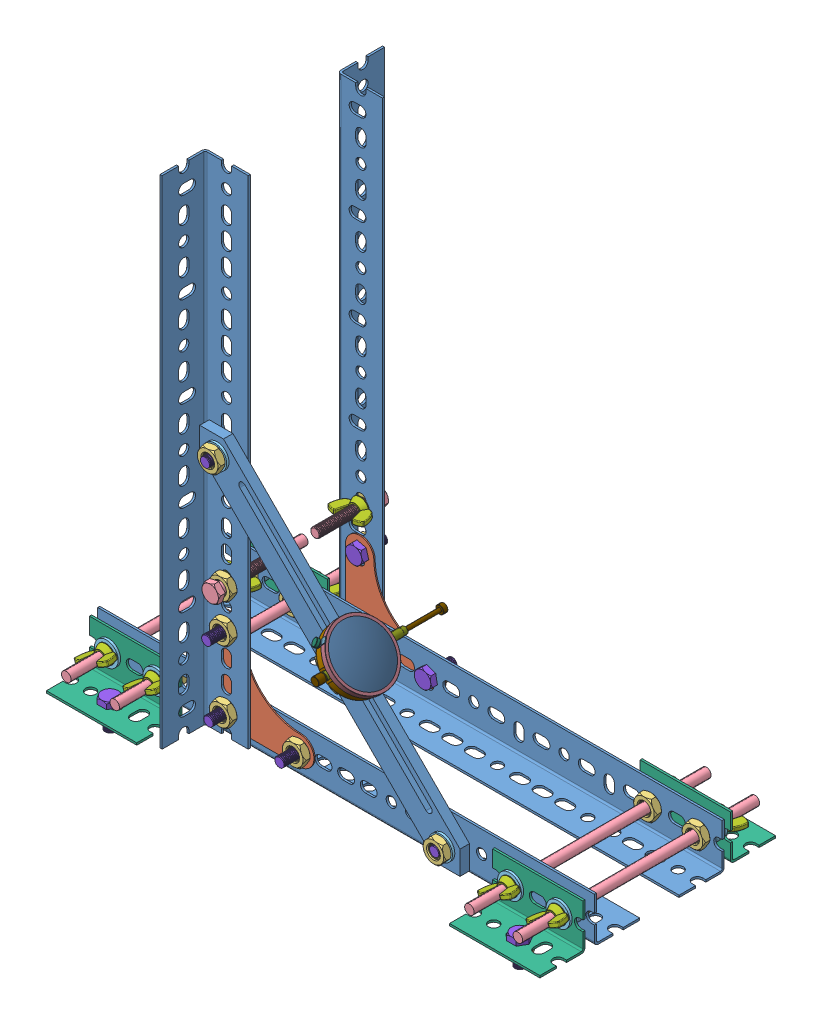
SolidWorks assembly WheelTruingStand, configuration Default. Lengths in mm.
Overall size (419.1 438.26 204.12).
125 component instances, 22 part files, 178 mates.
Components (placement in the parent):
- UprightsSlottedAngle-1: UprightsSlottedAngle [Default] at (103.66 10.7722 357.4461) size (38.1 419.1 38.1)
- UprightsSlottedAngle-2: UprightsSlottedAngle [Default] at (103.66 10.7722 468.9248) x (0 0 1) z (-1 0 0) size (38.1 419.1 38.1)
- UprightsSlottedAngle-3: UprightsSlottedAngle [Default] at (12.0168 9.9594 467.9248) x (0 0 -1) z (0 -1 0) size (38.1 419.1 38.1)
- UprightsSlottedAngle-4: UprightsSlottedAngle [Default] at (12.0168 9.9594 358.4461) x (0 1 0) z (0 0 -1) size (38.1 419.1 38.1)
- 90^CornerPlateSlottedAngle-1: 90^CornerPlateSlottedAngle [Default] at (12.0168 9.9594 467.9248) x (0 -1 0) z (0 0 1) size (83.94 83.94 1)
- 90^CornerPlateSlottedAngle-2: 90^CornerPlateSlottedAngle [Default] at (12.0168 9.9594 357.4461) x (0 -1 0) z (0 0 1) size (83.94 83.94 1)
- M8Nut-1: M8Nut [Default] at (123.5228 89.7662 476.7028) x (1 0 0) z (0 1 0) size (22 6.04 17.32)
- M8Nut-2: M8Nut [Default] at (123.5228 29.8222 476.7028) x (1 0 0) z (0 1 0) size (22 6.04 17.32)
- M8Nut-3: M8Nut [Default] at (123.5228 89.7662 349.6681) x (1 0 0) z (0 -1 0) size (22 6.04 17.32)
- M8Nut-4: M8Nut [Default] at (183.4668 29.8222 351.4461) x (1 0 0) z (0 -1 0) size (22 6.04 17.32)
- M8Nut-5: M8Nut [Default] at (123.5228 29.8222 349.6681) x (1 0 0) z (0 -1 0) size (22 6.04 17.32)
- M8X200mmThreadRod-2: M8X200mmThreadRod [Default] at (10.2975 4.4523 313.5466) size (8 8 200)
- M8X200mmThreadRod-3: M8X200mmThreadRod [Default] at (43.5006 13.543 313.5466) x (0.934051 -0.357141 0) z (0 0 1) size (8 8 200)
- M8X200mmThreadRod-4: M8X200mmThreadRod [Default] at (390.0297 3.0003 313.5466) x (0.268672 0.963232 0) z (0 0 1) size (8 8 200)
- M8X200mmThreadRod-5: M8X200mmThreadRod [Default] at (391.2975 4.4523 313.5466) size (8 8 200)
- M8Nut-6: M8Nut [Default] at (412.0668 29.8222 366.2241) x (1 0 0) z (0 1 0) size (22 6.04 17.32)
- M8Nut-7: M8Nut [Default] at (412.0668 29.8222 466.1468) x (1 0 0) z (0 1 0) size (22 6.04 17.32)
- M8Nut-8: M8Nut [Default] at (371.1728 29.8222 366.2241) x (1 0 0) z (0 1 0) size (22 6.04 17.32)
- M8Nut-9: M8Nut [Default] at (371.1728 29.8222 466.1468) x (1 0 0) z (0 1 0) size (22 6.04 17.32)
- M8Nut-10: M8Nut [Default] at (31.0668 29.8222 366.2241) x (1 0 0) z (0 1 0) size (22 6.04 17.32)
- M8Nut-11: M8Nut [Default] at (31.0668 29.8222 466.1468) x (1 0 0) z (0 1 0) size (22 6.04 17.32)
- M8Nut-12: M8Nut [Default] at (71.9608 29.8222 460.1468) x (0.923728 0.383049 0) z (0.383049 -0.923728 0) size (22 6.04 17.32)
- M8Nut-13: M8Nut [Default] at (71.9608 29.8222 366.2241) x (1 0 0) z (0 1 0) size (22 6.04 17.32)
- M8WashersX4-1: M8WashersX4 [Default] at (12.0168 9.9594 467.9248) x (0 -1 0) z (0 0 1) size (26.68 26.68 8)
  - M8Washer-1: M8Washer [Default] at origin size (20 20 2)
  - M8Washer-2: M8Washer [Default] at (349.4622 245.0224 6) x (0.432292 0.901734 0) z (0 0 1) size (20 20 2)
  - M8Washer-3: M8Washer [Default] at (360.8166 275.48 4) x (0.357751 0.933817 0) z (0 0 1) size (20 20 2)
  - M8Washer-4: M8Washer [Default] at (378.356 356.9651 2) x (0.156736 0.987641 0) z (0 0 1) size (20 20 2)
- M8WashersX4-2: M8WashersX4 [Default] at (391.0356 -370.2278 350.4461) size (26.68 26.68 8)
  - M8Washer-1: M8Washer [Default] at origin size (20 20 2)
  - M8Washer-2: M8Washer [Default] at (349.4622 245.0224 6) x (0.432292 0.901734 0) z (0 0 1) size (20 20 2)
  - M8Washer-3: M8Washer [Default] at (360.8166 275.48 4) x (0.357751 0.933817 0) z (0 0 1) size (20 20 2)
  - M8Washer-4: M8Washer [Default] at (378.356 356.9651 2) x (0.156736 0.987641 0) z (0 0 1) size (20 20 2)
- M8WashersX4-3: M8WashersX4 [Default] at (391.0356 -370.2278 467.9248) size (26.68 26.68 8)
  - M8Washer-1: M8Washer [Default] at origin size (20 20 2)
  - M8Washer-2: M8Washer [Default] at (349.4622 245.0224 6) x (0.432292 0.901734 0) z (0 0 1) size (20 20 2)
  - M8Washer-3: M8Washer [Default] at (360.8166 275.48 4) x (0.357751 0.933817 0) z (0 0 1) size (20 20 2)
  - M8Washer-4: M8Washer [Default] at (378.356 356.9651 2) x (0.156736 0.987641 0) z (0 0 1) size (20 20 2)
- M8WashersX4-4: M8WashersX4 [Default] at (91.8236 -370.2278 467.9248) size (26.68 26.68 8)
  - M8Washer-1: M8Washer [Default] at origin size (20 20 2)
  - M8Washer-2: M8Washer [Default] at (349.4622 245.0224 6) x (0.432292 0.901734 0) z (0 0 1) size (20 20 2)
  - M8Washer-3: M8Washer [Default] at (360.8166 275.48 4) x (0.357751 0.933817 0) z (0 0 1) size (20 20 2)
  - M8Washer-4: M8Washer [Default] at (378.356 356.9651 2) x (0.156736 0.987641 0) z (0 0 1) size (20 20 2)
- M8WashersX4-5: M8WashersX4 [Default] at (50.9296 -370.2278 467.9248) size (26.68 26.68 8)
  - M8Washer-1: M8Washer [Default] at origin size (20 20 2)
  - M8Washer-2: M8Washer [Default] at (349.4622 245.0224 6) x (0.432292 0.901734 0) z (0 0 1) size (20 20 2)
  - M8Washer-3: M8Washer [Default] at (360.8166 275.48 4) x (0.357751 0.933817 0) z (0 0 1) size (20 20 2)
  - M8Washer-4: M8Washer [Default] at (378.356 356.9651 2) x (0.156736 0.987641 0) z (0 0 1) size (20 20 2)
- M8WashersX4-6: M8WashersX4 [Default] at (50.9296 -370.2278 350.4461) size (26.68 26.68 8)
  - M8Washer-1: M8Washer [Default] at origin size (20 20 2)
  - M8Washer-2: M8Washer [Default] at (349.4622 245.0224 6) x (0.432292 0.901734 0) z (0 0 1) size (20 20 2)
  - M8Washer-3: M8Washer [Default] at (360.8166 275.48 4) x (0.357751 0.933817 0) z (0 0 1) size (20 20 2)
  - M8Washer-4: M8Washer [Default] at (378.356 356.9651 2) x (0.156736 0.987641 0) z (0 0 1) size (20 20 2)
- M8WashersX4-7: M8WashersX4 [Default] at (91.8236 -370.2278 350.4461) size (26.68 26.68 8)
  - M8Washer-1: M8Washer [Default] at origin size (20 20 2)
  - M8Washer-2: M8Washer [Default] at (349.4622 245.0224 6) x (0.432292 0.901734 0) z (0 0 1) size (20 20 2)
  - M8Washer-3: M8Washer [Default] at (360.8166 275.48 4) x (0.357751 0.933817 0) z (0 0 1) size (20 20 2)
  - M8Washer-4: M8Washer [Default] at (378.356 356.9651 2) x (0.156736 0.987641 0) z (0 0 1) size (20 20 2)
- M8WashersX4-8: M8WashersX4 [Default] at (431.9296 -370.2278 350.4461) size (26.68 26.68 8)
  - M8Washer-1: M8Washer [Default] at origin size (20 20 2)
  - M8Washer-2: M8Washer [Default] at (349.4622 245.0224 6) x (0.432292 0.901734 0) z (0 0 1) size (20 20 2)
  - M8Washer-3: M8Washer [Default] at (360.8166 275.48 4) x (0.357751 0.933817 0) z (0 0 1) size (20 20 2)
  - M8Washer-4: M8Washer [Default] at (378.356 356.9651 2) x (0.156736 0.987641 0) z (0 0 1) size (20 20 2)
- FeetSlottedAngle-1: FeetSlottedAngle [Default] at (91.0108 9.9594 475.9248) x (0 0 1) z (0 -1 0) size (38.1 76.2 38.1)
- FeetSlottedAngle-2: FeetSlottedAngle [Default] at (88.2168 9.9594 350.4461) x (0 1 0) z (0 0 1) size (38.1 76.2 38.1)
- FeetSlottedAngle-3: FeetSlottedAngle [Default] at (431.1168 9.9594 475.9248) x (0 0 1) z (0 -1 0) size (38.1 76.2 38.1)
- FeetSlottedAngle-4: FeetSlottedAngle [Default] at (352.1228 9.9594 350.4461) x (0 0 -1) z (0 -1 0) size (38.1 76.2 38.1)
- M8WingNut-2: M8WingNut [Default] at (412.0668 29.8222 346.6681) size (30.1 15.2 15.33)
- M8WingNut-3: M8WingNut [Default] at (371.1728 29.8222 346.6681) size (30.1 15.2 15.33)
- M8WingNut-4: M8WingNut [Default] at (371.1728 29.8222 479.7028) x (-0.923728 -0.383049 0) z (0 0 -1) size (30.1 15.2 15.33)
- M8WingNut-5: M8WingNut [Default] at (412.0668 29.8222 479.7028) x (-0.923728 -0.383049 0) z (0 0 -1) size (30.1 15.2 15.33)
- M8WingNut-6: M8WingNut [Default] at (31.0668 29.8222 479.7028) x (-0.923728 -0.383049 0) z (0 0 -1) size (30.1 15.2 15.33)
- M8WingNut-7: M8WingNut [Default] at (71.9608 29.8222 479.7028) x (-0.923728 -0.383049 0) z (0 0 -1) size (30.1 15.2 15.33)
- M8WingNut-8: M8WingNut [Default] at (31.0668 29.8222 346.6681) size (30.1 15.2 15.33)
- M8WingNut-9: M8WingNut [Default] at (71.9608 29.8222 346.6681) size (30.1 15.2 15.33)
- M8Washer-5: M8Washer [Default] at (391.0356 -370.2278 477.7028) size (20 20 2)
- M8Washer-6: M8Washer [Default] at (431.9296 -370.2278 477.7028) size (20 20 2)
- M8Washer-7: M8Washer [Default] at (431.9296 -370.2278 346.6681) size (20 20 2)
- M8Washer-8: M8Washer [Default] at (391.0356 -370.2278 346.6681) size (20 20 2)
- M8Washer-9: M8Washer [Default] at (91.8236 -370.2278 346.6681) size (20 20 2)
- M8Washer-10: M8Washer [Default] at (50.9296 -370.2278 346.6681) size (20 20 2)
- M8Washer-11: M8Washer [Default] at (50.9296 -370.2278 477.7028) size (20 20 2)
- M8Washer-12: M8Washer [Default] at (91.8236 -370.2278 477.7028) size (20 20 2)
- M8X30mmBolt-1: M8X30mmBolt [Default] at (395.8108 -38.1626 495.7876) size (17.6 25.23 13.86)
- M8X30mmBolt-2: M8X30mmBolt [Default] at (393.0168 -38.1626 330.5833) size (17.6 25.23 13.86)
- M8X30mmBolt-3: M8X30mmBolt [Default] at (50.1168 -38.1626 495.7876) size (17.6 25.23 13.86)
- M8X30mmBolt-4: M8X30mmBolt [Default] at (47.3228 -38.1626 330.5833) size (17.6 25.23 13.86)
- M8Nut-14: M8Nut [Default] at (393.0168 3.9594 330.5833) size (22 6.04 17.32)
- M8Nut-15: M8Nut [Default] at (395.8108 3.9594 495.7876) size (22 6.04 17.32)
- M8Nut-16: M8Nut [Default] at (47.3228 3.9594 330.5833) size (22 6.04 17.32)
- M8Nut-17: M8Nut [Default] at (50.1168 3.9594 495.7876) size (22 6.04 17.32)
- DialIndicator-1: DialIndicator [Default] at (242.5969 132.6801 480.9888) x (-0.707656 -0.706557 0) z (-0.706557 0.707656 0) size (34.28 109.24 70.95)
  - DialIndicatorHousing-1: DialIndicatorHousing [Default] at origin size (12.7 51.56 51.56)
  - DialIndicatorLense-1: DialIndicatorLense [Default] at (-1.8159 0 0) x (1 0 0) z (0 -0.851322 0.524644) size (4.54 51.56 51.56)
  - DialIndicatorDial-1: DialIndicatorDial [Default] at (-4.6592 0 0) x (0 -0.067556 0.997716) z (-1 0 0) size (45.14 45.14 0.76)
  - DialIndicatorNeedle-1: DialIndicatorNeedle [Default] at (-5.1672 0 0) x (0 -0.943918 0.330179) z (-1 0 0) size (2.35 22.8 0.25)
  - DialIndicatorBezel-1: DialIndicatorBezel [Default] at (-8.0314 0 0) x (1 0 0) z (0 0.990283 0.139064) size (4.81 52.36 52.36)
  - DialIndicatorFrictionTab-1: DialIndicatorFrictionTab [Default] at (-6.1789 21.5397 21.563) x (1 0 0) z (0 -0.707489 0.706725) size (10.93 1.28 4.57)
  - DialIndicatorThumbScrew-1: DialIndicatorThumbScrew [Default] at (-1.0637 18.4054 18.4491) x (0.995679 0.065702 -0.065631) z (0.092866 -0.704432 0.703671) size (6.42 4.9 6.42)
  - DialIndicatorPlungerSleeve-1: DialIndicatorPlungerSleeve [Default] at (-1.2717 3.1446 0) x (0.999846 0 0.017549) z (-0.017549 0 0.999846) size (6.35 68.78 6.35)
  - DialIndicatorBackMount-1: DialIndicatorBackMount [Default] at (6.7962 0 0) x (0 0 1) z (1 0 0) size (45.28 45.28 17.04)
  - DialIndicatorPlunger-1: DialIndicatorPlunger [Default] at (-1.2717 10.2115 0) x (-0.966446 0 -0.256869) z (0.256869 0 -0.966446) size (6.84 108.99 6.84)
- GaugeSlidingFixing-1: GaugeSlidingFixing [Default] at (103.66 10.7722 470.7028) size (219.59 219.9 8)
- M6X40mmBolt-1: M6X40mmBolt [Gwint po helisie] at (231.4964 121.5969 470.7028) x (-0.923728 -0.383049 0) z (0 0 -1) size (11.55 10 24.88)
- M6WingNut-1: M6WingNut [Default] at (231.4964 121.5969 483.2748) x (0.706557 -0.707656 0) z (0 0 -1) size (26.3 12.96 12.87)
- M8Washer-13: M8Washer [Default] at (333.8856 -370.2278 467.9248) size (20 20 2)
- M8X30mmBolt-5: M8X30mmBolt [Default] at (314.0228 29.8222 516.0468) x (0.979291 -0.202459 0) z (0.202459 0.979291 0) size (17.6 25.23 13.86)
- M8X30mmBolt-6: M8X30mmBolt [Default] at (123.5228 220.3222 518.8248) x (0.772622 -0.634867 0) z (0.634867 0.772622 0) size (17.6 25.23 13.86)
- M8Nut-18: M8Nut [Default] at (123.5228 220.3222 480.7028) x (0.998244 0.059232 0) z (0.059232 -0.998244 0) size (22 6.04 17.32)
- M8Nut-19: M8Nut [Default] at (314.0228 29.8222 480.7028) x (0.667325 0.744766 0) z (0.744766 -0.667325 0) size (22 6.04 17.32)
- M8Washer-14: M8Washer [Default] at (333.8856 -370.2278 478.7028) size (20 20 2)
- M8Washer-15: M8Washer [Default] at (143.3856 -179.7278 478.7028) size (20 20 2)
- M8X60mmBolt-1: M8X60mmBolt [Default] at (123.5228 122.2782 429.5652) x (0.675128 -0.737701 0) z (-0.737701 -0.675128 0) size (17.6 55.21 13.86)
- M8X60mmBolt-2: M8X60mmBolt [Default] at (123.5228 122.2782 396.1566) x (0.991664 -0.128854 0) z (0.128854 0.991664 0) size (17.6 55.21 13.86)
- M8Nut-20: M8Nut [Default] at (123.5228 122.2782 476.7028) x (1 0 0) z (0 1 0) size (22 6.04 17.32)
- M8Nut-21: M8Nut [Default] at (123.5228 122.2782 349.6681) x (1 0 0) z (0 -1 0) size (22 6.04 17.32)
- M8WingNut-10: M8WingNut [Default] at (123.5228 122.2782 468.9248) x (0.996087 -0.088381 0) z (0 0 1) size (30.1 15.2 15.33)
- M8WingNut-11: M8WingNut [Default] at (123.5228 122.2782 357.4461) x (-0.999027 -0.044093 0) z (0 0 -1) size (30.1 15.2 15.33)
- M8X30mmBolt-7: M8X30mmBolt [Default] at (123.5228 29.8222 516.0468) x (1 0 0) z (0 1 0) size (17.6 25.23 13.86)
- M8X30mmBolt-8: M8X30mmBolt [Default] at (123.5228 89.7662 517.8248) x (1 0 0) z (0 1 0) size (17.6 25.23 13.86)
- M8X30mmBolt-9: M8X30mmBolt [Default] at (183.4668 29.8222 516.0468) x (1 0 0) z (0 1 0) size (17.6 25.23 13.86)
- M8X30mmBolt-10: M8X30mmBolt [Default] at (123.5228 89.7662 308.5461) x (-0.283466 0.958982 0) z (0.958982 0.283466 0) size (17.6 25.23 13.86)
- M8X30mmBolt-11: M8X30mmBolt [Default] at (123.5228 29.8222 310.3241) x (0.309782 0.950808 0) z (0.950808 -0.309782 0) size (17.6 25.23 13.86)
- M8X30mmBolt-12: M8X30mmBolt [Default] at (183.4668 29.8222 310.3241) x (0.183215 -0.983073 0) z (-0.983073 -0.183215 0) size (17.6 25.23 13.86)
- M8Nut-22: M8Nut [Default] at (183.4668 29.8222 468.9248) x (1 0 0) z (0 -1 0) size (22 6.04 17.32)
Mates (geometry in assembly coordinates):
- Parallel5: parallel anti-aligned: line of UprightsSlottedAngle-3 through (431.1003 13.1344 466.1468) axis (-1 0 0); line of UprightsSlottedAngle-4 through (12.0168 11.7374 396.5461) axis (1 0 0)
- Parallel6: parallel anti-aligned: plane of UprightsSlottedAngle-3 through (926.4168 48.0594 467.9248) normal (0 0 1); plane of UprightsSlottedAngle-4 through (926.4168 13.1344 358.4461) normal (0 0 -1)
- Coincident9: coincident aligned: plane of UprightsSlottedAngle-3 through (926.4168 48.0594 467.9248) normal (0 1 0); plane of UprightsSlottedAngle-4 through (926.4168 48.0594 360.2241) normal (0 1 0)
- Coincident11: coincident aligned: line of UprightsSlottedAngle-3 through (12.0168 11.7374 429.8248) axis (0 0 1); line of UprightsSlottedAngle-4 through (12.0168 11.7374 382.6269) axis (0 0 1)
- Parallel9: parallel anti-aligned: plane of UprightsSlottedAngle-1 through (106.835 925.1722 357.4461) normal (0 0 1); plane of UprightsSlottedAngle-2 through (141.76 925.1722 468.9248) normal (0 0 -1)
- Parallel10: parallel aligned: plane of UprightsSlottedAngle-1 through (141.76 925.1722 355.6681) normal (1 0 0); plane of UprightsSlottedAngle-2 through (141.76 925.1722 468.9248) normal (1 0 0)
- Parallel11: parallel aligned: plane of UprightsSlottedAngle-2 through (106.835 10.7722 472.0998) normal (0 -1 0); plane of UprightsSlottedAngle-3 through (926.4168 9.9594 464.7498) normal (0 -1 0)
- Concentric2: concentric anti-aligned: circle of UprightsSlottedAngle-1; circle of UprightsSlottedAngle-2
- Concentric3: concentric aligned: circle of UprightsSlottedAngle-3; circle of UprightsSlottedAngle-4
- Concentric4: concentric anti-aligned: cylinder of UprightsSlottedAngle-2 through (123.5228 29.8222 468.9248) axis (0 0 1) radius 4.318; cylinder of UprightsSlottedAngle-3 through (123.5228 29.8222 467.9248) axis (0 0 -1) radius 4.318
- InPlace1: in place: plane of ? through (926.4168 48.0594 480.1633) normal (0 0 1); plane of ? through (0 0 480.1633) normal (0 0 1); moOrthogonalPlaneRef_w of ? through (926.4168 48.0594 480.1633) normal (0 0 1); plane of ? through (0 0 480.1633) normal (0 1 0); plane of ? through (926.4168 48.0594 480.1633) normal (0 0 1); plane of ? through (0 0 480.1633) normal (1 0 0); plane of UprightsSlottedAngle-3 through (926.4168 48.0594 467.9248) normal (0 0 1); unknown of ?
- Coincident27: coincident aligned: plane of UprightsSlottedAngle-3; plane of 90^CornerPlateSlottedAngle-1
- Coincident28: coincident aligned: moOrthogonalPlaneRef_w of UprightsSlottedAngle-3 through (12.0168 9.9594 467.9248) normal (1 0 0); plane of 90^CornerPlateSlottedAngle-1
- Coincident29: coincident anti-aligned: moOrthogonalPlaneRef_w of UprightsSlottedAngle-3 through (12.0168 9.9594 467.9248) normal (0 1 0); plane of 90^CornerPlateSlottedAngle-1
- Concentric5: concentric anti-aligned: circle of UprightsSlottedAngle-4; circle of 90^CornerPlateSlottedAngle-2
- Parallel14: parallel aligned: line of UprightsSlottedAngle-4 through (12.0168 13.1344 358.4461) axis (1 0 0); line of 90^CornerPlateSlottedAngle-2 through (123.5228 17.8222 357.4461) axis (1 0 0)
- Coincident32: coincident anti-aligned: plane of UprightsSlottedAngle-4 through (926.4168 13.1344 358.4461) normal (0 0 -1); plane of 90^CornerPlateSlottedAngle-2 through (123.5228 89.7662 358.4461) normal (0 0 1)
- Coincident33: coincident anti-aligned: plane of UprightsSlottedAngle-1 through (106.835 925.1722 357.4461) normal (0 0 1); plane of 90^CornerPlateSlottedAngle-2 through (123.5228 89.7662 357.4461) normal (0 0 -1)
- Coincident34: coincident anti-aligned: plane of UprightsSlottedAngle-2 through (141.76 925.1722 468.9248) normal (0 0 -1); plane of 90^CornerPlateSlottedAngle-1 through (123.5228 89.7662 468.9248) normal (0 0 1)
- Coincident43: coincident aligned: circle of UprightsSlottedAngle-2; plane of M8Nut-2 through (123.5228 29.8222 470.7028) normal (0 0 -1)
- Concentric12: concentric anti-aligned: circle of UprightsSlottedAngle-2; circle of M8Nut-2
- Coincident44: coincident anti-aligned: plane of UprightsSlottedAngle-2 through (141.76 925.1722 470.7028) normal (0 0 1); plane of M8Nut-1 through (123.5228 89.7662 470.7028) normal (0 0 -1)
- Concentric13: concentric anti-aligned: circle of UprightsSlottedAngle-2; circle of M8Nut-1
- Coincident45: coincident anti-aligned: plane of UprightsSlottedAngle-1 through (106.835 925.1722 355.6681) normal (0 0 -1); plane of M8Nut-3 through (123.5228 89.7662 355.6681) normal (0 0 1)
- Concentric14: concentric anti-aligned: circle of UprightsSlottedAngle-1; circle of M8Nut-3
- Coincident46: coincident anti-aligned: plane of UprightsSlottedAngle-1 through (106.835 925.1722 355.6681) normal (0 0 -1); plane of M8Nut-5 through (123.5228 29.8222 355.6681) normal (0 0 1)
- Concentric15: concentric anti-aligned: circle of UprightsSlottedAngle-1; circle of M8Nut-5
- Coincident47: coincident anti-aligned: plane of 90^CornerPlateSlottedAngle-2 through (123.5228 89.7662 357.4461) normal (0 0 -1); plane of M8Nut-4 through (183.4668 29.8222 357.4461) normal (0 0 1)
- Concentric16: concentric anti-aligned: circle of 90^CornerPlateSlottedAngle-2; circle of M8Nut-4
- Concentric22: concentric aligned: circle of UprightsSlottedAngle-4; cylinder of M8X200mmThreadRod-5 through (412.0668 29.8222 513.5466) axis (0 0 -1) radius 4
- Coincident52: coincident aligned: plane of M8X200mmThreadRod-5 through (412.0668 29.8222 313.5466) normal (0 0 -1); plane of M8X200mmThreadRod-4 through (371.1728 29.8222 313.5466) normal (0 0 -1)
- Coincident53: coincident aligned: plane of M8X200mmThreadRod-5 through (412.0668 29.8222 313.5466) normal (0 0 -1); plane of M8X200mmThreadRod-3 through (71.9608 29.8222 313.5466) normal (0 0 -1)
- Coincident54: coincident aligned: plane of M8X200mmThreadRod-5 through (412.0668 29.8222 313.5466) normal (0 0 -1); plane of M8X200mmThreadRod-2 through (31.0668 29.8222 313.5466) normal (0 0 -1)
- Concentric23: concentric aligned: circle of UprightsSlottedAngle-3; cylinder of M8X200mmThreadRod-2 through (31.0668 29.8222 513.5466) axis (0 0 -1) radius 4
- Concentric24: concentric aligned: circle of UprightsSlottedAngle-3; cylinder of M8X200mmThreadRod-3 through (71.9608 29.8222 513.5466) axis (0 0 -1) radius 4
- Concentric25: concentric aligned: circle of UprightsSlottedAngle-3; cylinder of M8X200mmThreadRod-4 through (371.1728 29.8222 513.5466) axis (0 0 -1) radius 4
- Concentric26: concentric anti-aligned: cylinder of M8X200mmThreadRod-5 through (412.0668 29.8222 513.5466) axis (0 0 -1) radius 4; circle of M8Nut-7
- Concentric27: concentric anti-aligned: cylinder of M8X200mmThreadRod-5 through (412.0668 29.8222 513.5466) axis (0 0 -1) radius 4; circle of M8Nut-6
- Concentric28: concentric anti-aligned: cylinder of M8X200mmThreadRod-4 through (371.1728 29.8222 513.5466) axis (0 0 -1) radius 4; circle of M8Nut-9
- Concentric29: concentric anti-aligned: cylinder of M8X200mmThreadRod-4 through (371.1728 29.8222 513.5466) axis (0 0 -1) radius 4; circle of M8Nut-8
- Concentric30: concentric aligned: cylinder of M8X200mmThreadRod-3 through (71.9608 29.8222 513.5466) axis (0 0 -1) radius 4; circle of M8Nut-12
- Concentric31: concentric anti-aligned: cylinder of M8X200mmThreadRod-3 through (71.9608 29.8222 513.5466) axis (0 0 -1) radius 4; circle of M8Nut-13
- Concentric32: concentric anti-aligned: cylinder of M8X200mmThreadRod-2 through (31.0668 29.8222 513.5466) axis (0 0 -1) radius 4; circle of M8Nut-11
- Concentric33: concentric anti-aligned: cylinder of M8X200mmThreadRod-2 through (31.0668 29.8222 513.5466) axis (0 0 -1) radius 4; circle of M8Nut-10
- Coincident55: coincident anti-aligned: plane of M8Nut-13 through (71.9608 29.8222 360.2241) normal (0 0 -1); plane of UprightsSlottedAngle-4 through (926.4168 13.1344 360.2241) normal (0 0 1)
- Coincident56: coincident anti-aligned: plane of M8Nut-12 through (71.9608 29.8222 466.1468) normal (0 0 1); plane of UprightsSlottedAngle-3 through (926.4168 48.0594 466.1468) normal (0 0 -1)
- Coincident57: coincident anti-aligned: plane of UprightsSlottedAngle-4 through (926.4168 13.1344 360.2241) normal (0 0 1); plane of M8Nut-10 through (31.0668 29.8222 360.2241) normal (0 0 -1)
- Coincident58: coincident anti-aligned: plane of UprightsSlottedAngle-4 through (926.4168 13.1344 360.2241) normal (0 0 1); plane of M8Nut-8 through (371.1728 29.8222 360.2241) normal (0 0 -1)
- Coincident59: coincident anti-aligned: plane of UprightsSlottedAngle-4 through (926.4168 13.1344 360.2241) normal (0 0 1); plane of M8Nut-6 through (412.0668 29.8222 360.2241) normal (0 0 -1)
- Coincident60: coincident anti-aligned: plane of UprightsSlottedAngle-3 through (926.4168 48.0594 466.1468) normal (0 0 -1); plane of M8Nut-7 through (412.0668 29.8222 466.1468) normal (0 0 1)
- Coincident61: coincident anti-aligned: plane of UprightsSlottedAngle-3 through (926.4168 48.0594 466.1468) normal (0 0 -1); plane of M8Nut-9 through (371.1728 29.8222 466.1468) normal (0 0 1)
- Coincident62: coincident anti-aligned: plane of UprightsSlottedAngle-3 through (926.4168 48.0594 466.1468) normal (0 0 -1); plane of M8Nut-11 through (31.0668 29.8222 466.1468) normal (0 0 1)
- Concentric37: concentric anti-aligned: cylinder of M8X200mmThreadRod-5 through (412.0668 29.8222 513.5466) axis (0 0 -1) radius 4; unknown of M8WashersX4-1/M8Washer-2
- Concentric38: concentric anti-aligned: cylinder of M8X200mmThreadRod-5 through (412.0668 29.8222 513.5466) axis (0 0 -1) radius 4; unknown of M8WashersX4-1/M8Washer-3
- Concentric39: concentric anti-aligned: cylinder of M8X200mmThreadRod-5 through (412.0668 29.8222 513.5466) axis (0 0 -1) radius 4; unknown of M8WashersX4-1/M8Washer-4
- Coincident69: coincident anti-aligned: plane of UprightsSlottedAngle-3 through (926.4168 48.0594 467.9248) normal (0 0 1); plane of M8WashersX4-3/M8Washer-1 through (371.1728 29.8222 467.9248) normal (0 0 -1)
- Coincident70: coincident anti-aligned: plane of UprightsSlottedAngle-3 through (926.4168 48.0594 467.9248) normal (0 0 1); plane of M8WashersX4-4/M8Washer-1 through (71.9608 29.8222 467.9248) normal (0 0 -1)
- Coincident71: coincident anti-aligned: plane of UprightsSlottedAngle-3 through (926.4168 48.0594 467.9248) normal (0 0 1); plane of M8WashersX4-5/M8Washer-1 through (31.0668 29.8222 467.9248) normal (0 0 -1)
- Concentric40: concentric anti-aligned: cylinder of M8X200mmThreadRod-2 through (31.0668 29.8222 513.5466) axis (0 0 -1) radius 4; circle of M8WashersX4-5/M8Washer-2
- Concentric41: concentric anti-aligned: cylinder of M8X200mmThreadRod-3 through (71.9608 29.8222 513.5466) axis (0 0 -1) radius 4; circle of M8WashersX4-4/M8Washer-2
- Concentric42: concentric anti-aligned: cylinder of M8X200mmThreadRod-4 through (371.1728 29.8222 513.5466) axis (0 0 -1) radius 4; circle of M8WashersX4-3/M8Washer-2
- Coincident72: coincident anti-aligned: plane of UprightsSlottedAngle-4 through (926.4168 13.1344 358.4461) normal (0 0 -1); plane of M8WashersX4-2/M8Washer-2 through (371.1728 29.8222 358.4461) normal (0 0 1)
- Coincident73: coincident anti-aligned: plane of UprightsSlottedAngle-4 through (926.4168 13.1344 358.4461) normal (0 0 -1); plane of M8WashersX4-8/M8Washer-2 through (412.0668 29.8222 358.4461) normal (0 0 1)
- Coincident74: coincident anti-aligned: plane of UprightsSlottedAngle-4 through (926.4168 13.1344 358.4461) normal (0 0 -1); plane of M8WashersX4-6/M8Washer-2 through (31.0668 29.8222 358.4461) normal (0 0 1)
- Coincident75: coincident anti-aligned: plane of UprightsSlottedAngle-4 through (926.4168 13.1344 358.4461) normal (0 0 -1); plane of M8WashersX4-7/M8Washer-2 through (71.9608 29.8222 358.4461) normal (0 0 1)
- Concentric43: concentric anti-aligned: cylinder of M8X200mmThreadRod-5 through (412.0668 29.8222 513.5466) axis (0 0 -1) radius 4; circle of M8WashersX4-8/M8Washer-1
- Concentric44: concentric anti-aligned: cylinder of M8X200mmThreadRod-4 through (371.1728 29.8222 513.5466) axis (0 0 -1) radius 4; circle of M8WashersX4-2/M8Washer-1
- Concentric45: concentric anti-aligned: cylinder of M8X200mmThreadRod-2 through (31.0668 29.8222 513.5466) axis (0 0 -1) radius 4; circle of M8WashersX4-6/M8Washer-1
- Concentric46: concentric anti-aligned: cylinder of M8X200mmThreadRod-3 through (71.9608 29.8222 513.5466) axis (0 0 -1) radius 4; circle of M8WashersX4-7/M8Washer-1
- Coincident76: coincident anti-aligned: plane of UprightsSlottedAngle-3 through (926.4168 48.0594 467.9248) normal (0 0 1); plane of M8WashersX4-1/M8Washer-1 through (412.0668 29.8222 467.9248) normal (0 0 -1)
- Coincident80: coincident anti-aligned: plane of M8WashersX4-5/M8Washer-2 through (31.0668 29.8222 475.9248) normal (0 0 1); plane of FeetSlottedAngle-1 through (-823.3892 48.0594 475.9248) normal (0 0 -1)
- Concentric47: concentric anti-aligned: circle of M8X200mmThreadRod-2; circle of FeetSlottedAngle-1
- Coincident86: coincident anti-aligned: plane of M8WashersX4-1/M8Washer-2 through (412.0668 29.8222 475.9248) normal (0 0 1); plane of FeetSlottedAngle-3 through (-483.2832 48.0594 475.9248) normal (0 0 -1)
- Concentric49: concentric aligned: cylinder of M8X200mmThreadRod-5 through (412.0668 29.8222 513.5466) axis (0 0 -1) radius 4; circle of FeetSlottedAngle-3
- Coincident89: coincident aligned: plane of UprightsSlottedAngle-4 through (926.4168 48.0594 360.2241) normal (0 1 0); plane of FeetSlottedAngle-4 through (1266.5228 48.0594 350.4461) normal (0 1 0)
- Coincident92: coincident anti-aligned: plane of M8WashersX4-8/M8Washer-1 through (412.0668 29.8222 350.4461) normal (0 0 -1); plane of FeetSlottedAngle-4 through (1266.5228 48.0594 350.4461) normal (0 0 1)
- Concentric50: concentric anti-aligned: cylinder of M8X200mmThreadRod-5 through (412.0668 29.8222 513.5466) axis (0 0 -1) radius 4; circle of FeetSlottedAngle-4
- Coincident93: coincident aligned: plane of UprightsSlottedAngle-4 through (12.0168 13.1344 361.6211) normal (-1 0 0); plane of FeetSlottedAngle-2 through (12.0168 79.9782 312.3461) normal (-1 0 0)
- Coincident94: coincident anti-aligned: plane of M8WashersX4-6/M8Washer-1 through (31.0668 29.8222 350.4461) normal (0 0 -1); plane of FeetSlottedAngle-2 through (-826.1832 13.1344 350.4461) normal (0 0 1)
- Concentric51: concentric anti-aligned: cylinder of M8X200mmThreadRod-2 through (31.0668 29.8222 513.5466) axis (0 0 -1) radius 4; circle of FeetSlottedAngle-2
- Coincident95: coincident anti-aligned: plane of FeetSlottedAngle-1 through (-823.3892 48.0594 477.7028) normal (0 0 1); plane of M8Washer-11 through (31.0668 29.8222 477.7028) normal (0 0 -1)
- Coincident96: coincident anti-aligned: plane of FeetSlottedAngle-1 through (-823.3892 48.0594 477.7028) normal (0 0 1); plane of M8Washer-12 through (71.9608 29.8222 477.7028) normal (0 0 -1)
- Coincident97: coincident anti-aligned: plane of FeetSlottedAngle-1 through (-823.3892 48.0594 477.7028) normal (0 0 1); plane of M8Washer-5 through (371.1728 29.8222 477.7028) normal (0 0 -1)
- Coincident98: coincident anti-aligned: plane of FeetSlottedAngle-1 through (-823.3892 48.0594 477.7028) normal (0 0 1); plane of M8Washer-6 through (412.0668 29.8222 477.7028) normal (0 0 -1)
- Concentric52: concentric anti-aligned: circle of M8Washer-6; cylinder of M8X200mmThreadRod-5 through (412.0668 29.8222 513.5466) axis (0 0 -1) radius 4
- Concentric53: concentric anti-aligned: circle of M8Washer-5; cylinder of M8X200mmThreadRod-4 through (371.1728 29.8222 513.5466) axis (0 0 -1) radius 4
- Concentric54: concentric anti-aligned: cylinder of M8X200mmThreadRod-3 through (71.9608 29.8222 513.5466) axis (0 0 -1) radius 4; circle of M8Washer-12
- Concentric55: concentric anti-aligned: cylinder of M8X200mmThreadRod-2 through (31.0668 29.8222 513.5466) axis (0 0 -1) radius 4; circle of M8Washer-11
- Coincident99: coincident anti-aligned: plane of M8Washer-11 through (31.0668 29.8222 479.7028) normal (0 0 1); plane of M8WingNut-7 through (71.9608 29.8222 479.7028) normal (0 0 -1)
- Coincident100: coincident anti-aligned: plane of M8Washer-11 through (31.0668 29.8222 479.7028) normal (0 0 1); plane of M8WingNut-6 through (31.0668 29.8222 479.7028) normal (0 0 -1)
- Coincident101: coincident anti-aligned: plane of M8Washer-11 through (31.0668 29.8222 479.7028) normal (0 0 1); plane of M8WingNut-4 through (371.1728 29.8222 479.7028) normal (0 0 -1)
- Coincident102: coincident anti-aligned: plane of M8Washer-11 through (31.0668 29.8222 479.7028) normal (0 0 1); plane of M8WingNut-5 through (412.0668 29.8222 479.7028) normal (0 0 -1)
- Concentric56: concentric aligned: cylinder of M8X200mmThreadRod-5 through (412.0668 29.8222 513.5466) axis (0 0 -1) radius 4; circle of M8WingNut-5
- Concentric57: concentric aligned: cylinder of M8X200mmThreadRod-4 through (371.1728 29.8222 513.5466) axis (0 0 -1) radius 4; circle of M8WingNut-4
- Concentric58: concentric aligned: cylinder of M8X200mmThreadRod-3 through (71.9608 29.8222 513.5466) axis (0 0 -1) radius 4; circle of M8WingNut-7
- Concentric59: concentric aligned: cylinder of M8X200mmThreadRod-2 through (31.0668 29.8222 513.5466) axis (0 0 -1) radius 4; circle of M8WingNut-6
- Coincident103: coincident anti-aligned: plane of FeetSlottedAngle-2 through (-826.1832 13.1344 348.6681) normal (0 0 -1); plane of M8Washer-9 through (71.9608 29.8222 348.6681) normal (0 0 1)
- Coincident104: coincident anti-aligned: plane of FeetSlottedAngle-2 through (-826.1832 13.1344 348.6681) normal (0 0 -1); plane of M8Washer-10 through (31.0668 29.8222 348.6681) normal (0 0 1)
- Coincident105: coincident anti-aligned: plane of FeetSlottedAngle-2 through (-826.1832 13.1344 348.6681) normal (0 0 -1); plane of M8Washer-7 through (412.0668 29.8222 348.6681) normal (0 0 1)
- Coincident106: coincident anti-aligned: plane of FeetSlottedAngle-2 through (-826.1832 13.1344 348.6681) normal (0 0 -1); plane of M8Washer-8 through (371.1728 29.8222 348.6681) normal (0 0 1)
- Concentric60: concentric anti-aligned: circle of M8Washer-7; cylinder of M8X200mmThreadRod-5 through (412.0668 29.8222 513.5466) axis (0 0 -1) radius 4
- Concentric61: concentric anti-aligned: cylinder of M8X200mmThreadRod-4 through (371.1728 29.8222 513.5466) axis (0 0 -1) radius 4; circle of M8Washer-8
- Concentric62: concentric anti-aligned: cylinder of M8X200mmThreadRod-3 through (71.9608 29.8222 513.5466) axis (0 0 -1) radius 4; circle of M8Washer-9
- Concentric63: concentric anti-aligned: cylinder of M8X200mmThreadRod-2 through (31.0668 29.8222 513.5466) axis (0 0 -1) radius 4; circle of M8Washer-10
- Coincident107: coincident anti-aligned: plane of M8Washer-10 through (31.0668 29.8222 346.6681) normal (0 0 -1); plane of M8WingNut-8 through (31.0668 29.8222 346.6681) normal (0 0 1)
- Coincident108: coincident anti-aligned: plane of M8Washer-10 through (31.0668 29.8222 346.6681) normal (0 0 -1); plane of M8WingNut-9 through (71.9608 29.8222 346.6681) normal (0 0 1)
- Coincident109: coincident anti-aligned: plane of M8Washer-10 through (31.0668 29.8222 346.6681) normal (0 0 -1); plane of M8WingNut-3 through (371.1728 29.8222 346.6681) normal (0 0 1)
- Coincident110: coincident anti-aligned: plane of M8Washer-10 through (31.0668 29.8222 346.6681) normal (0 0 -1); plane of M8WingNut-2 through (412.0668 29.8222 346.6681) normal (0 0 1)
- Concentric64: concentric anti-aligned: cylinder of M8X200mmThreadRod-5 through (412.0668 29.8222 513.5466) axis (0 0 -1) radius 4; circle of M8WingNut-2
- Concentric65: concentric anti-aligned: cylinder of M8X200mmThreadRod-4 through (371.1728 29.8222 513.5466) axis (0 0 -1) radius 4; circle of M8WingNut-3
- Concentric66: concentric anti-aligned: cylinder of M8X200mmThreadRod-2 through (31.0668 29.8222 513.5466) axis (0 0 -1) radius 4; circle of M8WingNut-8
- Concentric67: concentric anti-aligned: cylinder of M8X200mmThreadRod-3 through (71.9608 29.8222 513.5466) axis (0 0 -1) radius 4; circle of M8WingNut-9
- Coincident111: coincident anti-aligned: plane of FeetSlottedAngle-1 through (-823.3892 11.7374 479.0998) normal (0 1 0); plane of M8X30mmBolt-3 through (50.1168 11.7374 495.7876) normal (0 -1 0)
- Coincident112: coincident anti-aligned: plane of FeetSlottedAngle-1 through (-823.3892 11.7374 479.0998) normal (0 1 0); plane of M8X30mmBolt-4 through (47.3228 11.7374 330.5833) normal (0 -1 0)
- Coincident113: coincident anti-aligned: plane of FeetSlottedAngle-1 through (-823.3892 11.7374 479.0998) normal (0 1 0); plane of M8X30mmBolt-1 through (395.8108 11.7374 495.7876) normal (0 -1 0)
- Coincident114: coincident anti-aligned: plane of FeetSlottedAngle-1 through (-823.3892 11.7374 479.0998) normal (0 1 0); plane of M8X30mmBolt-2 through (393.0168 11.7374 330.5833) normal (0 -1 0)
- Concentric68: concentric aligned: circle of M8X30mmBolt-2; circle of FeetSlottedAngle-4
- Concentric69: concentric aligned: circle of FeetSlottedAngle-3; circle of M8X30mmBolt-1
- Concentric70: concentric aligned: circle of FeetSlottedAngle-1; circle of M8X30mmBolt-3
- Concentric71: concentric anti-aligned: circle of FeetSlottedAngle-2; circle of M8X30mmBolt-4
- Coincident116: coincident anti-aligned: plane of FeetSlottedAngle-4 through (1266.5228 9.9594 347.2711) normal (0 -1 0); plane of M8Nut-14 through (393.0168 9.9594 330.5833) normal (0 1 0)
- Coincident117: coincident anti-aligned: plane of FeetSlottedAngle-4 through (1266.5228 9.9594 347.2711) normal (0 -1 0); plane of M8Nut-15 through (395.8108 9.9594 495.7876) normal (0 1 0)
- Coincident118: coincident anti-aligned: plane of FeetSlottedAngle-4 through (1266.5228 9.9594 347.2711) normal (0 -1 0); plane of M8Nut-16 through (47.3228 9.9594 330.5833) normal (0 1 0)
- Coincident119: coincident anti-aligned: plane of FeetSlottedAngle-4 through (1266.5228 9.9594 347.2711) normal (0 -1 0); plane of M8Nut-17 through (50.1168 9.9594 495.7876) normal (0 1 0)
- Concentric72: concentric aligned: circle of FeetSlottedAngle-1; circle of M8Nut-17
- Concentric73: concentric anti-aligned: circle of FeetSlottedAngle-2; circle of M8Nut-16
- Concentric74: concentric aligned: circle of FeetSlottedAngle-4; circle of M8Nut-14
- Concentric75: concentric aligned: circle of FeetSlottedAngle-3; circle of M8Nut-15
- InPlace4: in place: plane of ? through (141.76 925.1722 467.7923) normal (0 0 1); plane of ? through (0 0 467.7923) normal (0 0 1); plane of ? through (141.76 925.1722 467.7923) normal (0 0 1); plane of ? through (0 0 467.7923) normal (0 1 0); plane of ? through (141.76 925.1722 467.7923) normal (0 0 1); plane of ? through (0 0 467.7923) normal (1 0 0); plane of UprightsSlottedAngle-2 through (141.76 925.1722 470.7028) normal (0 0 1); unknown of GaugeSlidingFixing-1
- Coincident120: coincident aligned: plane of UprightsSlottedAngle-2; plane of GaugeSlidingFixing-1
- Coincident121: coincident aligned: moOrthogonalPlaneRef_w of UprightsSlottedAngle-2 through (103.66 10.7722 470.7028) normal (0 1 0); plane of GaugeSlidingFixing-1 through (103.66 10.7722 470.7028) normal (0 1 0)
- Coincident122: coincident anti-aligned: moOrthogonalPlaneRef_w of UprightsSlottedAngle-2 through (103.66 10.7722 470.7028) normal (-1 0 0); plane of GaugeSlidingFixing-1 through (103.66 10.7722 470.7028) normal (1 0 0)
- Coincident123: coincident anti-aligned: plane of DialIndicator-1/DialIndicatorBackMount-1 through (237.7875 127.8782 478.7028) normal (0 0 -1); plane of GaugeSlidingFixing-1 through (103.66 10.7722 478.7028) normal (0 0 1)
- Parallel24: parallel anti-aligned: plane of DialIndicator-1/DialIndicatorBackMount-1 through (237.7875 127.8782 480.9888) normal (-0.707656 -0.706557 0); plane of GaugeSlidingFixing-1 through (328.4231 35.1343 478.7028) normal (0.707656 0.706557 0)
- Width1: width anti-aligned: plane of GaugeSlidingFixing-1 through (146.883 210.5879 470.7028) normal (-0.707656 -0.706557 0); plane of GaugeSlidingFixing-1 through (142.637 206.3485 470.7028) normal (0.707656 0.706557 0); cylinder of DialIndicator-1/DialIndicatorBackMount-1 through (231.4964 121.5969 478.7028) axis (0 0 1) radius 3.175
- Coincident125: coincident anti-aligned: plane of GaugeSlidingFixing-1 through (103.66 10.7722 470.7028) normal (0 0 -1); plane of M6X40mmBolt-1 through (231.4964 121.5969 470.7028) normal (0 0 1)
- Concentric76: concentric aligned: cylinder of DialIndicator-1/DialIndicatorBackMount-1 through (231.4964 121.5969 478.7028) axis (0 0 1) radius 3.175; circle of M6X40mmBolt-1
- Concentric77: concentric aligned: circle of DialIndicator-1/DialIndicatorBackMount-1; circle of M6WingNut-1
- Coincident126: coincident anti-aligned: plane of DialIndicator-1/DialIndicatorBackMount-1 through (233.3009 132.3718 483.2748) normal (0 0 1); plane of M6WingNut-1 through (231.4964 121.5969 483.2748) normal (0 0 -1)
- Parallel25: parallel aligned: plane of GaugeSlidingFixing-1 through (146.883 210.5879 470.7028) normal (-0.707656 -0.706557 0); plane of M6WingNut-1 through (225.7539 125.0485 488.9746) normal (-0.707656 -0.706557 0)
- Concentric78: concentric anti-aligned: cylinder of GaugeSlidingFixing-1 through (314.0228 29.8222 478.7028) axis (0 0 -1) radius 5; circle of M8Washer-13
- Coincident128: coincident anti-aligned: plane of UprightsSlottedAngle-3 through (926.4168 48.0594 467.9248) normal (0 0 1); plane of M8Washer-13 through (314.0228 29.8222 467.9248) normal (0 0 -1)
- Concentric79: concentric anti-aligned: cylinder of GaugeSlidingFixing-1 through (314.0228 29.8222 478.7028) axis (0 0 -1) radius 5; circle of M8X30mmBolt-5
- Concentric80: concentric anti-aligned: cylinder of GaugeSlidingFixing-1 through (123.5228 220.3222 478.7028) axis (0 0 -1) radius 5; circle of M8X30mmBolt-6
- Coincident129: coincident anti-aligned: plane of UprightsSlottedAngle-2 through (141.76 925.1722 468.9248) normal (0 0 -1); plane of M8X30mmBolt-6 through (123.5228 220.3222 468.9248) normal (0 0 1)
- Coincident130: coincident anti-aligned: plane of UprightsSlottedAngle-3 through (926.4168 48.0594 466.1468) normal (0 0 -1); plane of M8X30mmBolt-5 through (314.0228 29.8222 466.1468) normal (0 0 1)
- Coincident131: coincident anti-aligned: plane of GaugeSlidingFixing-1 through (103.66 10.7722 478.7028) normal (0 0 1); plane of M8Washer-14 through (314.0228 29.8222 478.7028) normal (0 0 -1)
- Concentric81: concentric aligned: circle of GaugeSlidingFixing-1; circle of M8Washer-14
- Concentric82: concentric anti-aligned: circle of M8Nut-19; circle of M8Washer-14
- Coincident132: coincident anti-aligned: plane of M8Nut-19 through (314.0228 29.8222 480.7028) normal (0 0 -1); plane of M8Washer-14 through (314.0228 29.8222 480.7028) normal (0 0 1)
- Coincident133: coincident anti-aligned: plane of GaugeSlidingFixing-1 through (103.66 10.7722 478.7028) normal (0 0 1); plane of M8Washer-15 through (123.5228 220.3222 478.7028) normal (0 0 -1)
- Concentric83: concentric aligned: circle of GaugeSlidingFixing-1; circle of M8Washer-15
- Concentric84: concentric anti-aligned: circle of M8Nut-18; circle of M8Washer-15
- Coincident134: coincident anti-aligned: plane of M8Nut-18 through (123.5228 220.3222 480.7028) normal (0 0 -1); plane of M8Washer-15 through (123.5228 220.3222 480.7028) normal (0 0 1)
- Concentric86: concentric anti-aligned: circle of UprightsSlottedAngle-2; circle of M8Nut-20
- Concentric87: concentric anti-aligned: circle of UprightsSlottedAngle-2; circle of M8WingNut-10
- Coincident135: coincident anti-aligned: plane of UprightsSlottedAngle-2 through (141.76 925.1722 470.7028) normal (0 0 1); plane of M8Nut-20 through (123.5228 122.2782 470.7028) normal (0 0 -1)
- Coincident136: coincident anti-aligned: plane of UprightsSlottedAngle-2 through (141.76 925.1722 468.9248) normal (0 0 -1); plane of M8WingNut-10 through (123.5228 122.2782 468.9248) normal (0 0 1)
- Concentric89: concentric anti-aligned: circle of UprightsSlottedAngle-1; circle of M8Nut-21
- Concentric90: concentric anti-aligned: circle of UprightsSlottedAngle-1; circle of M8WingNut-11
- Coincident137: coincident anti-aligned: plane of UprightsSlottedAngle-1 through (106.835 925.1722 355.6681) normal (0 0 -1); plane of M8Nut-21 through (123.5228 122.2782 355.6681) normal (0 0 1)
- Coincident138: coincident anti-aligned: plane of UprightsSlottedAngle-1 through (106.835 925.1722 357.4461) normal (0 0 1); plane of M8WingNut-11 through (123.5228 122.2782 357.4461) normal (0 0 -1)
- Concentric91: concentric anti-aligned: circle of M8X60mmBolt-1; circle of M8Nut-20
- Concentric92: concentric anti-aligned: circle of M8X60mmBolt-2; circle of M8Nut-21
- Concentric93: concentric anti-aligned: circle of UprightsSlottedAngle-2; circle of M8X30mmBolt-7
- Concentric94: concentric aligned: circle of 90^CornerPlateSlottedAngle-1; circle of M8X30mmBolt-9
- Concentric95: concentric aligned: circle of M8Nut-1; circle of M8X30mmBolt-8
- Coincident140: coincident anti-aligned: plane of 90^CornerPlateSlottedAngle-1 through (123.5228 89.7662 467.9248) normal (0 0 -1); plane of M8X30mmBolt-8 through (123.5228 89.7662 467.9248) normal (0 0 1)
- Coincident141: coincident anti-aligned: plane of UprightsSlottedAngle-3 through (926.4168 48.0594 466.1468) normal (0 0 -1); plane of M8X30mmBolt-7 through (123.5228 29.8222 466.1468) normal (0 0 1)
- Coincident142: coincident anti-aligned: plane of UprightsSlottedAngle-3 through (926.4168 48.0594 466.1468) normal (0 0 -1); plane of M8X30mmBolt-9 through (183.4668 29.8222 466.1468) normal (0 0 1)
- Concentric96: concentric anti-aligned: cylinder of M8X30mmBolt-9 through (183.4668 29.8222 466.0468) axis (0 0 1) radius 4; circle of M8Nut-22
- Coincident143: coincident anti-aligned: plane of 90^CornerPlateSlottedAngle-1 through (123.5228 89.7662 468.9248) normal (0 0 1); plane of M8Nut-22 through (183.4668 29.8222 468.9248) normal (0 0 -1)
- Concentric97: concentric aligned: circle of M8Nut-4; circle of M8X30mmBolt-12
- Concentric98: concentric aligned: circle of M8Nut-5; circle of M8X30mmBolt-11
- Concentric99: concentric aligned: circle of M8Nut-3; circle of M8X30mmBolt-10
- Coincident145: coincident anti-aligned: plane of 90^CornerPlateSlottedAngle-2 through (123.5228 89.7662 358.4461) normal (0 0 1); plane of M8X30mmBolt-10 through (123.5228 89.7662 358.4461) normal (0 0 -1)
- Coincident146: coincident anti-aligned: plane of UprightsSlottedAngle-4 through (926.4168 13.1344 360.2241) normal (0 0 1); plane of M8X30mmBolt-12 through (183.4668 29.8222 360.2241) normal (0 0 -1)
- Coincident147: coincident anti-aligned: plane of UprightsSlottedAngle-4 through (926.4168 13.1344 360.2241) normal (0 0 1); plane of M8X30mmBolt-11 through (123.5228 29.8222 360.2241) normal (0 0 -1)
